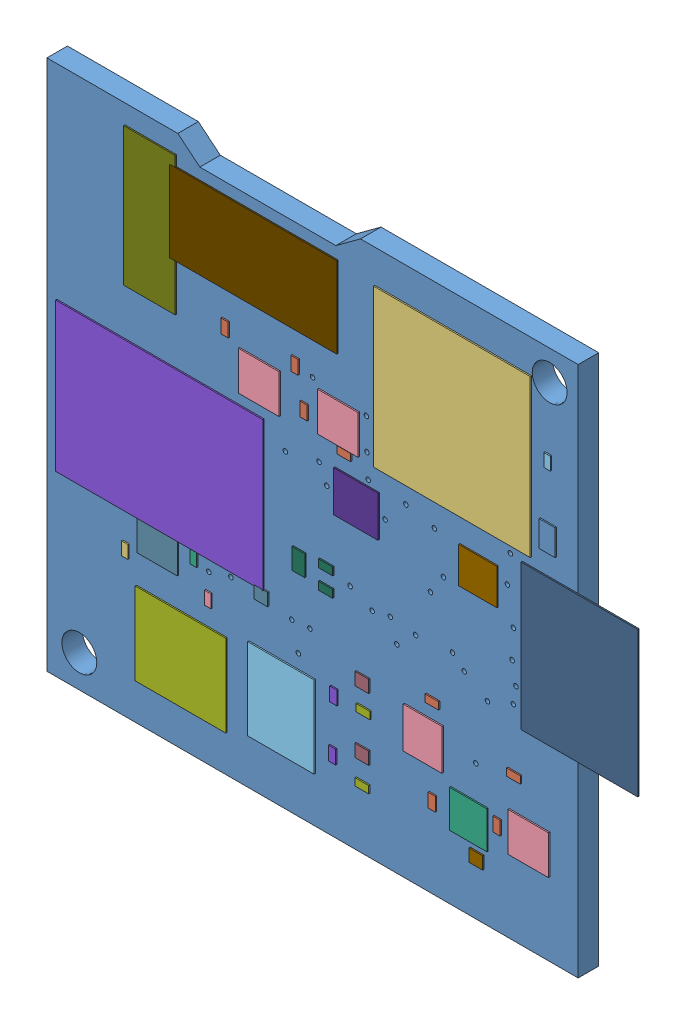
SolidWorks assembly PCB(2), configuration Default. Lengths in mm.
Overall size (45.7 41 1.78).
58 component instances, 33 part files, 0 mates.
Components (placement in the parent):
- PCB(2).step-1: PCB(2).step [Default] at origin size (45.7 41 1.78)
  - PCB Component.step-1: PCB Component.step [Default] at origin size (45.7 41 1.78)
    - Board.step-1: Board.step [Default] at origin size (41 41 1.58)
    - 2996TR.step-1: 2996TR.step [Default] at (40.14 34.65 0) x (1 0 0) z (0 0 -1) size (13.21 12.07 0.1)
    - 2996TR.step-2: 2996TR.step [Default] at (21.69 34.65 0) x (1 0 0) z (0 0 -1) size (13.21 12.07 0.1)
    - 2996TR.step-3: 2996TR.step [Default] at (20.86 59.95 0) x (-1 0 0) z (0 0 -1) size (13.21 12.07 0.1)
    - 2996TR.step-4: 2996TR.step [Default] at (39.96 59.63 0) x (-1 0 0) z (0 0 -1) size (13.21 12.07 0.1)
    - SCD41-D-R2.step-1: SCD41-D-R2.step [Default] at (41.35 59.4 1.584) size (12.1 12.1 0.1)
    - BSS138.step-1: BSS138.step [Default] at (39.94 37.09 1.584) size (3 3.14 0.1)
    - BSS138.step-2: BSS138.step [Default] at (47.24 35.01 1.584) x (0 1 0) z (0 0 1) size (3 3.14 0.1)
    - BSS138.step-3: BSS138.step [Default] at (26.44 55.43 1.584) x (0 1 0) z (0 0 1) size (3 3.14 0.1)
    - BSS138.step-4: BSS138.step [Default] at (32.54 55.75 1.584) x (0 1 0) z (0 0 1) size (3 3.14 0.1)
    - TSV912IDT.step-1: TSV912IDT.step [Default] at (28.16 33.68 1.584) x (0 -1 0) z (0 0 1) size (6.3 5.13 0.1)
    - SGP30.step-1: SGP30.step [Default] at (42.4 33.66 1.584) x (-1 0 0) z (0 0 1) size (2.88 2.88 0.1)
    - MICS-6814.step-1: MICS-6814.step [Default] at (20.41 33.71 1.584) x (0 1 0) z (0 0 1) size (6.34 7 0.1)
    - 317030213.step-1: 317030213.step [Default] at (18.77 47.25 1.584) x (0 1 0) z (0 0 1) size (11.45 16 0.1)
    - BME280.step-1: BME280.step [Default] at (43.18 50.09 1.584) size (2.95 2.77 0.1)
    - EG1213.step-1: EG1213.step [Default] at (48.7 47.1 1.584) x (0 1 0) z (0 0 1) size (11.2 9 0.1)
    - MC78LC50NTRGTSOT23-5_ONS.step-1: MC78LC50NTRGTSOT23-5_ONS.step [Default] at (29.4 47.4 0) x (-1 0 0) z (0 0 -1) size (2.79 3.33 0.1)
    - MIC5219-3.3YMMMSOP-8LD-PL-1_MCH.step-1: MIC5219-3.3YMMMSOP-8LD-PL-1_MCH.step [Default] at (36 47.2 0) x (-1 0 0) z (0 0 -1) size (4.9 3.53 0.1)
    - S-1318D18-M5T1U4.step-1: S-1318D18-M5T1U4.step [Default] at (43.3 46.3 0) x (1 0 0) z (0 0 -1) size (4.2 3.6 0.1)
    - MMBT3904-215.step-1: MMBT3904-215.step [Default] at (18.6 39.2 1.584) x (0 -1 0) z (0 0 1) size (3.16 3.12 0.1)
    - ECS-.327-9-16-TR.step-1: ECS-.327-9-16-TR.step [Default] at (29.5 44.1 1.584) x (0 -1 0) z (0 0 1) size (1.6 1 0.1)
    - BG306-04-A-1-0400-X-X_REVD.step-1: BG306-04-A-1-0400-X-X_REVD.step [Default] at (18 61.2 1.584) x (0 -1 0) z (0 0 1) size (10.66 4 0.1)
    - STMICROELECTRONICS_LIS3DHSTMICROELECTRONICS_LIS3DH_0_0.step-1: STMICROELECTRONICS_LIS3DHSTMICROELECTRONICS_LIS3DH_0_0.step [Default] at (33.8 50.2 1.584) x (-1 0 0) z (0 0 1) size (3.43 3.15 0.1)
    - S5B-ZR-SM4A-TF_(LF)_(SN)CONN_S5B-ZR-SM4A-TF_JST.step-1: S5B-ZR-SM4A-TF_(LF)_(SN)CONN_S5B-ZR-SM4A-TF_JST.step [Default] at (24.1 59.8 1.584) size (12.9 6.25 0.1)
    - LTST-C170KRKT.step-1: LTST-C170KRKT.step [Default] at (48.7 55.3 1.584) x (0 -1 0) z (0 0 1) size (2 1.25 0.1)
    - MCS0402MC1002FE000.step-1: MCS0402MC1002FE000.step [Default] at (39.8 33.2 1.584) x (0 -1 0) z (0 0 1) size (1.06 0.56 0.1)
    - MCS0402MC1002FE000.step-2: MCS0402MC1002FE000.step [Default] at (39.8 39.9 1.584) size (1.06 0.56 0.1)
    - MCS0402MC1002FE000.step-3: MCS0402MC1002FE000.step [Default] at (44.8 34.1 1.584) x (0 -1 0) z (0 0 1) size (1.06 0.56 0.1)
    - MCS0402MC1002FE000.step-4: MCS0402MC1002FE000.step [Default] at (46.1 38.1 1.584) x (-1 0 0) z (0 0 1) size (1.06 0.56 0.1)
    - MCS0402MC1002FE000.step-5: MCS0402MC1002FE000.step [Default] at (29.2 57.1 1.584) x (0 -1 0) z (0 0 1) size (1.06 0.56 0.1)
    - MCS0402MC1002FE000.step-6: MCS0402MC1002FE000.step [Default] at (33 53.1 1.584) size (1.06 0.56 0.1)
    - MCS0402MC1002FE000.step-7: MCS0402MC1002FE000.step [Default] at (23.8 56.9 1.584) x (0 1 0) z (0 0 1) size (1.06 0.56 0.1)
    - MCS0402MC1002FE000.step-8: MCS0402MC1002FE000.step [Default] at (29.9 54.4 1.584) x (0 1 0) z (0 0 1) size (1.06 0.56 0.1)
    - ERJPA2F1300X.step-1: ERJPA2F1300X.step [Default] at (16.1 38.2 1.584) x (0 1 0) z (0 0 1) size (1 0.5 0.1)
    - ERJPA2J821X.step-1: ERJPA2J821X.step [Default] at (22.5 38.1 1.584) x (0 1 0) z (0 0 1) size (1 0.5 0.1)
    - ERA2AEB331X.step-1: ERA2AEB331X.step [Default] at (48.7 60.4 1.584) x (0 -1 0) z (0 0 1) size (1 0.5 0.1)
    - ERJPA2F5101X.step-1: ERJPA2F5101X.step [Default] at (21.4 40.3 1.584) x (0 -1 0) z (0 0 1) size (1 0.5 0.1)
    - ERJ-2GEJ106X.step-1: ERJ-2GEJ106X.step [Default] at (34.5 36.6 1.584) size (1.06 0.56 0.1)
    - ERJ-2GEJ106X.step-2: ERJ-2GEJ106X.step [Default] at (34.4 31.6 1.584) x (-1 0 0) z (0 0 1) size (1.06 0.56 0.1)
    - ERJ-2GEJ106X.step-3: ERJ-2GEJ106X.step [Default] at (32.5 45.7 0) x (0 1 0) z (0 0 -1) size (1.06 0.56 0.1)
    - ERJ-2GEJ106X.step-4: ERJ-2GEJ106X.step [Default] at (33.4 43 0) x (0 -1 0) z (0 0 -1) size (1.06 0.56 0.1)
    - ERJ-2GEJ515X.step-1: ERJ-2GEJ515X.step [Default] at (32.2 36.5 1.584) x (0 -1 0) z (0 0 1) size (1.06 0.56 0.1)
    - ERJ-2GEJ515X.step-2: ERJ-2GEJ515X.step [Default] at (32.1 32.5 1.584) x (0 -1 0) z (0 0 1) size (1.06 0.56 0.1)
    - C0402C104K9RACAUTO.step-1: C0402C104K9RACAUTO.step [Default] at (32 47.8 0) x (0 1 0) z (0 0 -1) size (1.06 0.96 0.1)
    - C0402C104K9RACAUTO.step-2: C0402C104K9RACAUTO.step [Default] at (29.4 45.1 0) x (-1 0 0) z (0 0 -1) size (1.06 0.96 0.1)
    - C0402C104K9RACAUTO.step-3: C0402C104K9RACAUTO.step [Default] at (43.2 31.1 1.584) size (1.06 0.96 0.1)
    - CL05A225MQ5NNNC.step-1: CL05A225MQ5NNNC.step [Default] at (39.7 44.8 0) x (1 0 0) z (0 0 -1) size (1.06 0.96 0.1)
    - CL05B471KB5NNNCCAP_CL05_SAM.step-1: CL05B471KB5NNNCCAP_CL05_SAM.step [Default] at (36.1 44.8 0) x (1 0 0) z (0 0 -1) size (1 0.5 0.1)
    - JMK105BJ105KV-F.step-1: JMK105BJ105KV-F.step [Default] at (40.6 46.7 0) x (0 1 0) z (0 0 -1) size (1.06 0.56 0.1)
    - JMK105BJ105KV-F.step-2: JMK105BJ105KV-F.step [Default] at (43.6 43.7 0) x (1 0 0) z (0 0 -1) size (1.06 0.56 0.1)
    - CL05B103KO5NNNC.step-1: CL05B103KO5NNNC.step [Default] at (34.4 38.5 1.584) x (-1 0 0) z (0 0 1) size (1.06 0.96 0.1)
    - CL05B103KO5NNNC.step-2: CL05B103KO5NNNC.step [Default] at (34.4 33.7 1.584) size (1.06 0.96 0.1)
    - CL05B103KO5NNNC.step-3: CL05B103KO5NNNC.step [Default] at (32.1 43 0) x (0 -1 0) z (0 0 -1) size (1.06 0.96 0.1)
    - CL05A106MP5NUNC.step-1: CL05A106MP5NUNC.step [Default] at (26.6 40.4 1.584) x (-1 0 0) z (0 0 1) size (1.06 0.96 0.1)
    - 04025A120FAT2A.step-1: 04025A120FAT2A.step [Default] at (31.6 43.3 1.584) x (-1 0 0) z (0 0 1) size (1.1 0.6 0.1)
    - 04025A120FAT2A.step-2: 04025A120FAT2A.step [Default] at (31.6 44.8 1.584) x (-1 0 0) z (0 0 1) size (1.1 0.6 0.1)
